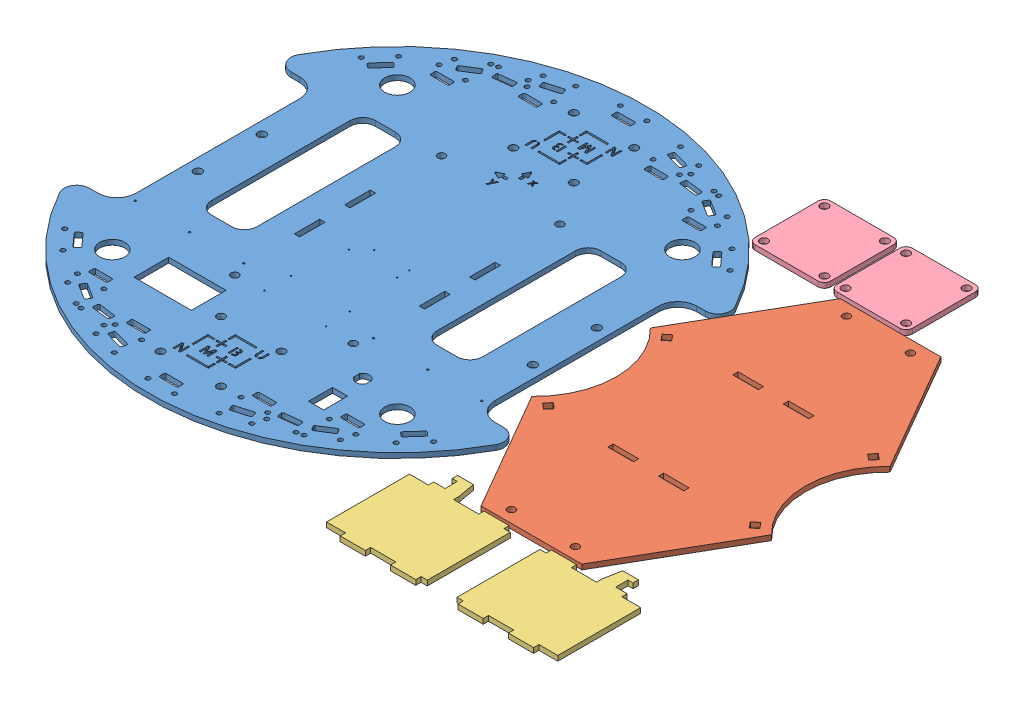
SolidWorks assembly laser_cut_assembly, configuration Default. Lengths in mm.
Overall size (519.01 4 424.89).
6 component instances, 4 part files, 14 mates.
Components (placement in the parent):
- frame_upper-1: frame_upper [Défaut] at origin size (348.98 4 395)
- frame_lower-1: frame_lower [Défaut] at (249.4022 0 0.5014) x (0 0 -1) z (1 0 0) size (285 4 190.25)
- frame_vertical-1: frame_vertical [Défaut] at (342.6488 4 215.3269) x (-1 0 0) z (0 0 1) size (80 4 88.2)
- frame_vertical-2: frame_vertical [Défaut] at (159.1155 0 215.3269) size (80 4 88.2)
- caster_spacer-1: caster_spacer [Default] at (163.5902 0 -175.3663) size (60 4 60)
- caster_spacer-2: caster_spacer [Default] at (228.4271 0 -175.3663) x (0 0 -1) z (1 0 0) size (60 4 60)
Mates (geometry in assembly coordinates):
- Coincident1: coincident anti-aligned: plane of caster_spacer-2 through (228.4271 0 -175.3663) normal (0 -1 0)
- Coincident2: coincident anti-aligned: plane of caster_spacer-1 through (163.5902 0 -175.3663) normal (0 -1 0)
- Coincident3: coincident anti-aligned: plane of frame_lower-1 through (249.4022 0 0.5014) normal (0 -1 0)
- Coincident5: coincident anti-aligned: plane of frame_vertical-2 through (159.1155 0 215.3269) normal (0 -1 0)
- Coincident6: coincident anti-aligned: plane of frame_upper-1 through (0 0 0) normal (0 -1 0)
- Coincident7: coincident aligned: plane of frame_upper-1 through (0 0 0) normal (0 0 1)
- Coincident8: coincident aligned: plane of frame_upper-1 through (0 0 0) normal (1 0 0)
- Coincident9: coincident anti-aligned: plane of frame_vertical-1 through (342.6488 0 215.3269) normal (0 -1 0)
- Parallel1: parallel aligned: plane of frame_vertical-1 through (262.6488 0 215.3269) normal (-1 0 0); plane of frame_vertical-2 through (159.1155 4 215.3269) normal (-1 0 0)
- Parallel2: parallel anti-aligned: plane of frame_upper-1 through (-97.5 4 50) normal (0 0 -1); plane of frame_lower-1 through (184.4022 4 143.0014) normal (0 0 1)
- Parallel5: parallel anti-aligned: plane of frame_lower-1 through (184.4022 4 -141.9986) normal (0 0 -1); plane of caster_spacer-2 through (258.4271 4 -145.3663) normal (0 0 1)
- Parallel8: parallel anti-aligned: plane of caster_spacer-1 through (193.5902 4 -145.3663) normal (1 0 0); plane of caster_spacer-2 through (198.4271 4 -145.3663) normal (-1 0 0)
- Coincident17: coincident aligned: plane of caster_spacer-1 through (133.5902 4 -205.3663) normal (0 0 -1); plane of caster_spacer-2 through (258.4271 4 -205.3663) normal (0 0 -1)
- Coincident18: coincident aligned: plane of frame_vertical-1 through (267.6488 0 219.5269) normal (0 0 1); plane of frame_vertical-2 through (234.1155 4 219.5269) normal (0 0 1)
